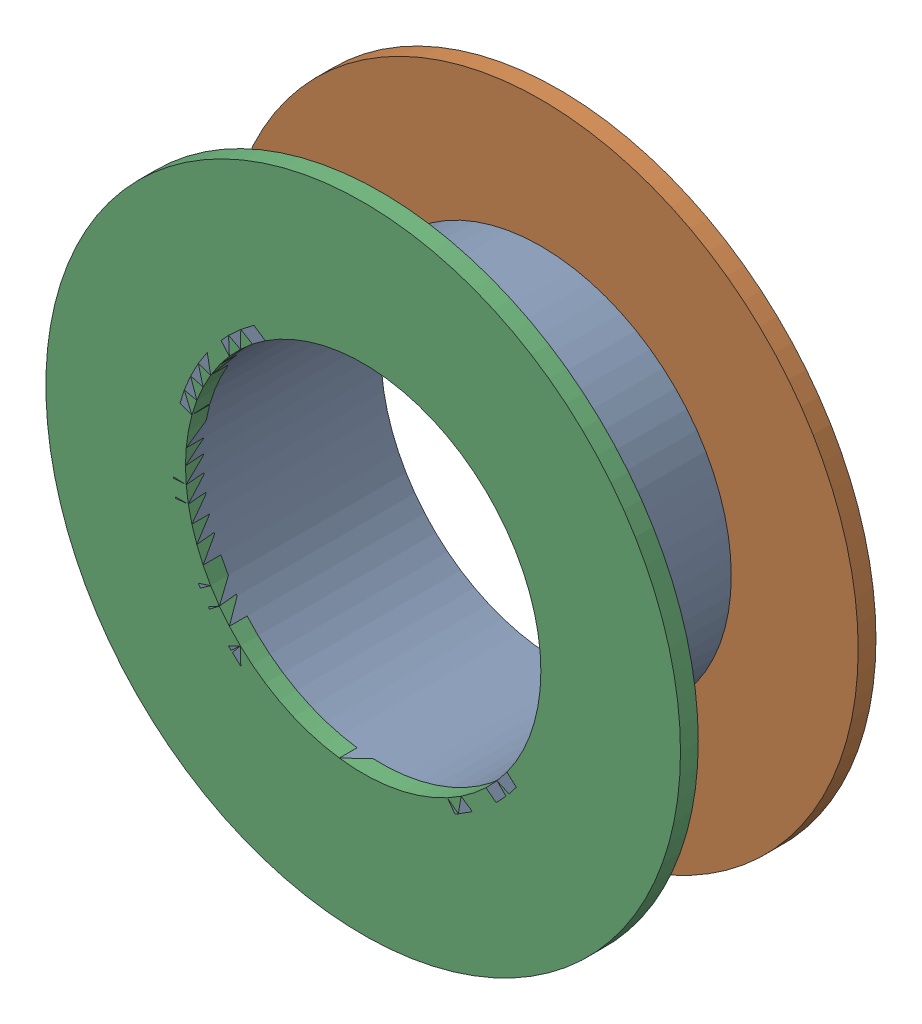
SolidWorks assembly Via (9.5mm,35.5mm) from Top Layer to Bottom Layer, configuration Predeterminado. Lengths in mm.
Overall size (1.27 1.27 0.39).
6 component instances, 2 part files, 0 mates.
Components (placement in the parent):
- Via Hole-1: Via Hole [Predeterminado] at (9.5 35.5 -0.4013) size (0.76 0.76 0.39)
  - Via Hole-Part-1-1: Via Hole-Part-1 [Predeterminado] at origin size (0.76 0.76 0.39)
- Via Top Layer-1: Via Top Layer [Predeterminado] at (9.5 35.5 -0.4013) size (1.27 1.27 0.04)
  - Via Top Layer-Part-1-1: Via Top Layer-Part-1 [Predeterminado] at origin size (1.27 1.27 0.04)
- Via Top Layer-2: Via Top Layer [Predeterminado] at (9.5 35.5 -0.0457) size (1.27 1.27 0.04)
  - Via Top Layer-Part-1-1: Via Top Layer-Part-1 [Predeterminado] at origin size (1.27 1.27 0.04)
